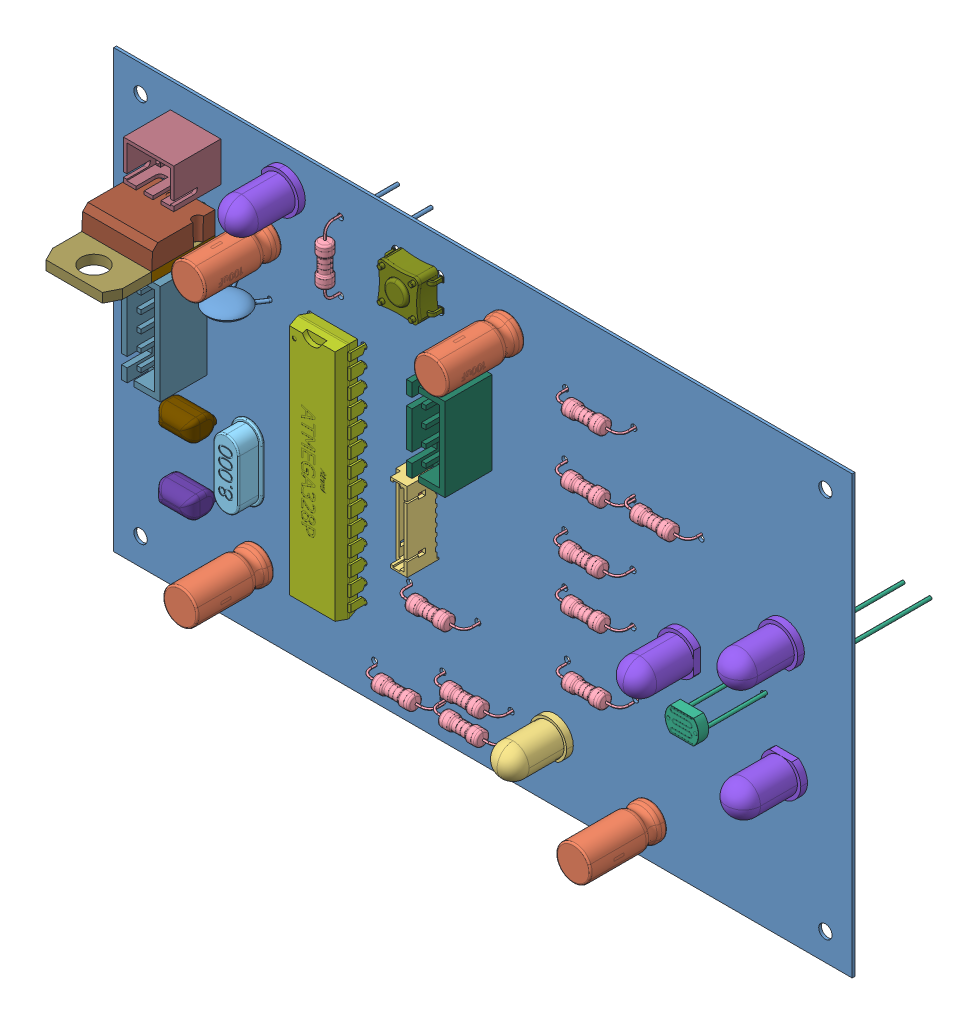
SolidWorks assembly 1, configuration Default. Lengths in mm.
Overall size (109.98 65.02 42.54).
46 component instances, 26 part files, 0 mates.
Components (placement in the parent):
- 1.step-1: 1.step [Default] at origin size (109.98 65.02 42.54)
  - Board.step-1: Board.step [Default] at origin size (109.98 65.02 0.41)
    - Open CASCADE STEP translator 6.8 2.1.1.step-1: Open CASCADE STEP translator 6.8 2.1.1.step [Default] at (0 0 -0.4115) size (109.98 65.02 0.41)
  - Free-Models.step-1: Free-Models.step [Default] at origin size (97.5 59.76 42.54)
    - JST_connector_1x8__P1.25mm_thru_hole_wafer_A2.step-1: JST_connector_1x8__P1.25mm_thru_hole_wafer_A2.step [Default] at (86.639 61.435 0) x (0 1 0) z (1 0 0) size (11.75 6.9 3.2)
      - pins.step-1: pins.step [Default] at origin size (9.25 5.4 0.75)
      - Open CASCADE STEP translator 6.8 2.2.40.2.step-1: Open CASCADE STEP translator 6.8 2.2.40.2.step [Default] at origin size (11.75 4.7 3.2)
    - regulator.step-1: regulator.step [Default] at (49.276 86.36 6) x (-1 0 0) z (0 1 0) size (10.43 0.01 1.4)
    - regulator-0.step-1: regulator-0.step [Default] at (49.276 86.36 6) x (-1 0 0) z (0 1 0) size (1.7 14 0.7)
    - regulator-1.step-1: regulator-1.step [Default] at (49.276 86.36 6) x (-1 0 0) z (0 1 0) size (1.7 14 0.7)
    - regulator-2.step-1: regulator-2.step [Default] at (49.276 86.36 6) x (-1 0 0) z (0 1 0) size (1.7 14 0.7)
    - regulator-3.step-1: regulator-3.step [Default] at (49.276 86.36 6) x (-1 0 0) z (0 1 0) size (10.4 9.42 0.03)
    - regulator-4.step-1: regulator-4.step [Default] at (49.276 86.36 6) x (-1 0 0) z (0 1 0) size (0.01 9.42 1.4)
    - regulator-5.step-1: regulator-5.step [Default] at (49.276 86.36 6) x (-1 0 0) z (0 1 0) size (0.01 9.42 1.4)
    - regulator-6.step-1: regulator-6.step [Default] at (49.276 86.36 6) x (-1 0 0) z (0 1 0) size (10.43 9.44 3.3)
    - regulator-7.step-1: regulator-7.step [Default] at (49.276 86.36 6) x (-1 0 0) z (0 1 0) size (10.4 15.75 1.4)
    - JST_B2B-XH-A_Through-hole_shrouded_header_top_entry_type.step-1: JST_B2B-XH-A_Through-hole_shrouded_header_top_entry_type.step [Default] at (50.419 96.491 0) x (-1 0 0) z (0 0 1) size (7.5 5.9 10.4)
    - B5B-XH-A.step-1: B5B-XH-A.step [Default] at (49.276 75.438 0) x (0 -1 0) z (-1 0 0) size (14.9 10.4 5.75)
    - B4B-XH-A.step-1: B4B-XH-A.step [Default] at (91.694 83.058 0) x (0 -1 0) z (-1 0 0) size (12.4 10.4 5.75)
    - Push_Button_Tactile.step-1: Push_Button_Tactile.step [Default] at (83.566 95.885 0) x (1 0 0) z (0 -1 0) size (7.66 3.5 6)
    - RDER71H105K2M1C03A.step-1: RDER71H105K2M1C03A.step [Default] at (50.8 52.705 2) x (1 0 0) z (0 -1 0) size (5.6 19.97 3.35)
    - RDER71H105K2M1C03A_1984339275.step-1: RDER71H105K2M1C03A_1984339275.step [Default] at (50.8 62.611 2) x (1 0 0) z (0 -1 0) size (5.51 19.97 3.33)
    - disccap.step-1: disccap.step [Default] at (59.0565 82.5638 4) x (1 0 0) z (0 0 -1) size (6.01 2.04 31)
    - 100uF.step-1: 100uF.step [Default] at (60.706 90.043 0) x (0 1 0) z (1 0 0) size (5.15 17.45 5.15)
    - 100uF.step-2: 100uF.step [Default] at (118.11 43.6559 0) x (1 0 0) z (0 -1 0) size (5.15 17.45 5.15)
    - 100uF.step-3: 100uF.step [Default] at (96.866 95.977 0) x (0 1 0) z (1 0 0) size (5.15 17.45 5.15)
    - CA_GRB_LED_5mm.step-1: CA_GRB_LED_5mm.step [Default] at (103.93 47.4375 0) x (0 -1 0) z (-1 0 0) size (5.12 34.2 5.5)
    - 100uF.step-4: 100uF.step [Default] at (59.563 47.4658 0) x (1 0 0) z (0 -1 0) size (5.15 17.45 5.15)
    - axial_resistor_6mm.step-1: axial_resistor_6mm.step [Default] at (110.236 74.236 2) x (1 0 0) z (0 -1 0) size (10.3 5.14 2.15)
    - axial_resistor_6mm.step-2: axial_resistor_6mm.step [Default] at (110.49 67.31 2) x (1 0 0) z (0 -1 0) size (10.3 5.14 2.15)
    - axial_resistor_6mm.step-3: axial_resistor_6mm.step [Default] at (110.49 83.439 2) x (1 0 0) z (0 -1 0) size (10.3 5.14 2.15)
    - axial_resistor_6mm.step-4: axial_resistor_6mm.step [Default] at (92.456 47.244 2) x (1 0 0) z (0 -1 0) size (10.3 5.14 2.15)
    - axial_resistor_6mm.step-5: axial_resistor_6mm.step [Default] at (71.696 93.218 2) x (0 1 0) z (1 0 0) size (10.3 5.14 2.15)
    - axial_resistor_6mm.step-6: axial_resistor_6mm.step [Default] at (110.617 92.837 2) x (1 0 0) z (0 -1 0) size (10.3 5.14 2.15)
    - axial_resistor_6mm.step-7: axial_resistor_6mm.step [Default] at (120.777 84.269 2) x (1 0 0) z (0 -1 0) size (10.3 5.14 2.15)
    - axial_resistor_6mm.step-8: axial_resistor_6mm.step [Default] at (87.376 55.948 2) x (1 0 0) z (0 -1 0) size (10.3 5.14 2.15)
    - axial_resistor_6mm.step-9: axial_resistor_6mm.step [Default] at (110.617 57.472 2) x (1 0 0) z (0 -1 0) size (10.3 5.14 2.15)
    - axial_resistor_6mm.step-10: axial_resistor_6mm.step [Default] at (92.329 43.502 2) x (1 0 0) z (0 -1 0) size (10.3 5.14 2.15)
    - axial_resistor_6mm.step-11: axial_resistor_6mm.step [Default] at (82.296 43.121 2) x (1 0 0) z (0 -1 0) size (10.3 5.14 2.15)
    - crystal_oscillator.step-1: crystal_oscillator.step [Default] at (58.42 60.071 0) x (0 1 0) z (1 0 0) size (11.05 6.5 4.65)
    - Part7.step-1: Part7.step [Default] at (133.35 68.602 9) x (1 0 0) z (0 -1 0) size (5 35.01 3.6)
    - ATMEGA328p.step-1: ATMEGA328p.step [Default] at (67.472 83.312 0) x (1 0 0) z (0 0 1) size (8.13 35.4 6.99)
    - LED_GREEN_5MM.step-1: LED_GREEN_5MM.step [Default] at (63.758 97.838 9) x (0 -1 0) z (0 0 -1) size (6 5.5 14)
    - LED_GREEN_5MM.step-2: LED_GREEN_5MM.step [Default] at (138.097 76.585 9) x (1 0 0) z (0 0 -1) size (6 5.5 14)
    - LED_GREEN_5MM.step-3: LED_GREEN_5MM.step [Default] at (123.103 67.993 9) x (0 1 0) z (0 0 -1) size (6 5.5 14)
    - LED_GREEN_5MM.step-4: LED_GREEN_5MM.step [Default] at (138.557 60.071 9) x (-1 0 0) z (0 0 -1) size (6 5.5 14)
